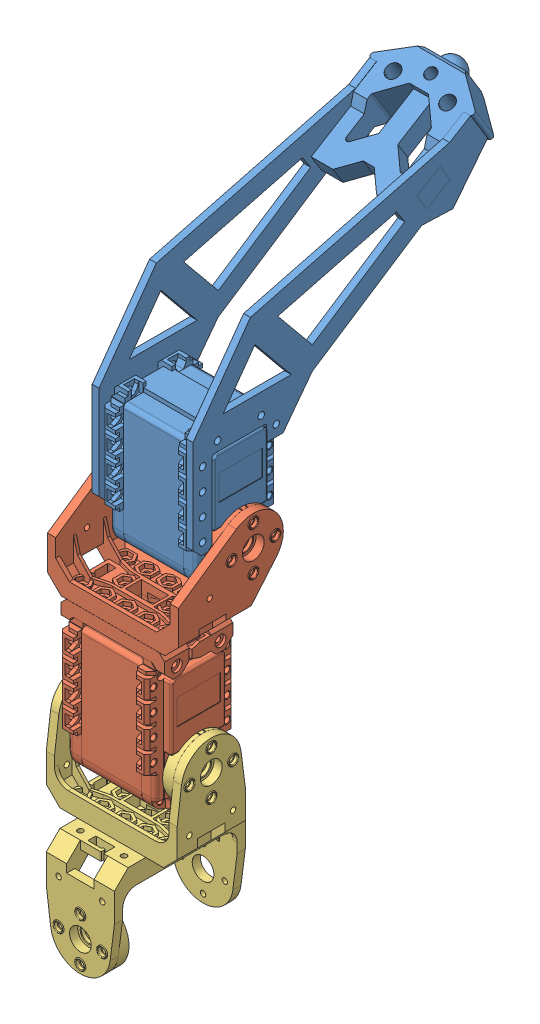
SolidWorks assembly Left_Leg, configuration Default. Lengths in mm.
Overall size (49.4 225.94 139).
3 component instances, 3 part files, 3 mates.
Components (placement in the parent):
- Tibia_left-3: Tibia_left [Default] at (15.2 117.5 -28.8423) x (0 0 1) z (1 0 0) size (117.7 108.98 38.67)
- Femur_left-3: Femur_left [Default] at (14.2997 53 -14.2997) x (0 0 1) z (1 0 0) size (42.04 87.04 48.5)
- Coxa_left-3: Coxa_left [Default] at origin size (48.5 75 48.5)
Mates (geometry in assembly coordinates):
- Coincident12: coordinate: point of Coxa_left-3; point of assembly
- Coincident13: coordinate: point of Femur_left-3; point of assembly
- Coincident14: coordinate: point of Tibia_left-3; point of Femur_left-3
